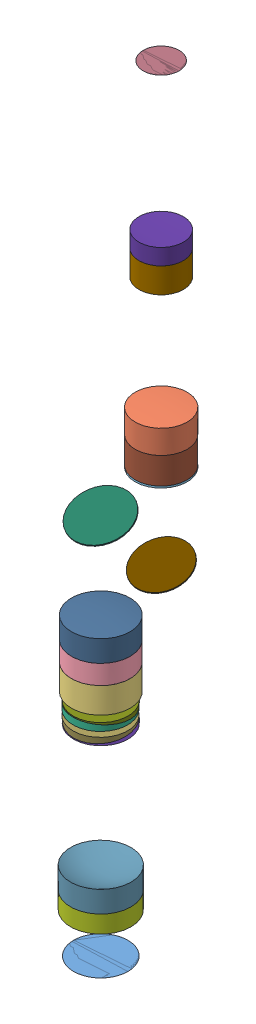
SolidWorks assembly magellan330, configuration Default. Lengths in mm.
Overall size (155.26 1776.66 280.63).
18 component instances, 18 part files, 5 mates.
Components (placement in the parent):
- Imported-1: Imported [Default] at origin size (129.21 0 129.21)
- Imported1-1: Imported1 [Default] at origin size (130.2 75 126.39)
- Imported2-1: Imported2 [Default] at origin size (146.3 77.14 142.72)
- Imported3-1: Imported3 [Default] at origin size (149.56 73 142.04)
- Imported4-1: Imported4 [Default] at origin size (130.63 33.15 125.86)
- Imported5-1: Imported5 [Default] at origin size (130 15.83 130)
- Imported6-1: Imported6 [Default] at origin size (151.81 64.55 146.78)
- Imported7-1: Imported7 [Default] at origin size (130 15.83 130)
- Imported8-1: Imported8 [Default] at origin size (109.58 70 108.08)
- Imported9-1: Imported9 [Default] at origin size (146.2 68.67 142.73)
- Imported10-1: Imported10 [Default] at origin size (134.1 94.07 126.31)
- Imported11-1: Imported11 [Default] at origin size (130 15.75 130.94)
- Imported12-1: Imported12 [Default] at origin size (85.29 0 85.29)
- Imported13-1: Imported13 [Default] at origin size (152.25 74.98 146.77)
- Imported14-1: Imported14 [Default] at origin size (129.97 46.89 123.02)
- Imported15-1: Imported15 [Default] at origin size (130 15.75 130.94)
- Imported16-1: Imported16 [Default] at origin size (109.31 46.69 107.59)
- Imported17-1: Imported17 [Default] at origin size (121.56 43.86 115.06)
Mates (geometry in assembly coordinates):
- Coincident1: coincident: point of Imported-1; point of Imported1-1
- Parallel1: parallel: plane of Imported-1; plane of Imported1-1
- Parallel2: parallel: plane of Imported-1; plane of Imported2-1
- Parallel3: parallel aligned: plane of Imported-1; plane of Imported1-1
- Coincident5: coincident: point of Imported-1; point of Imported2-1
